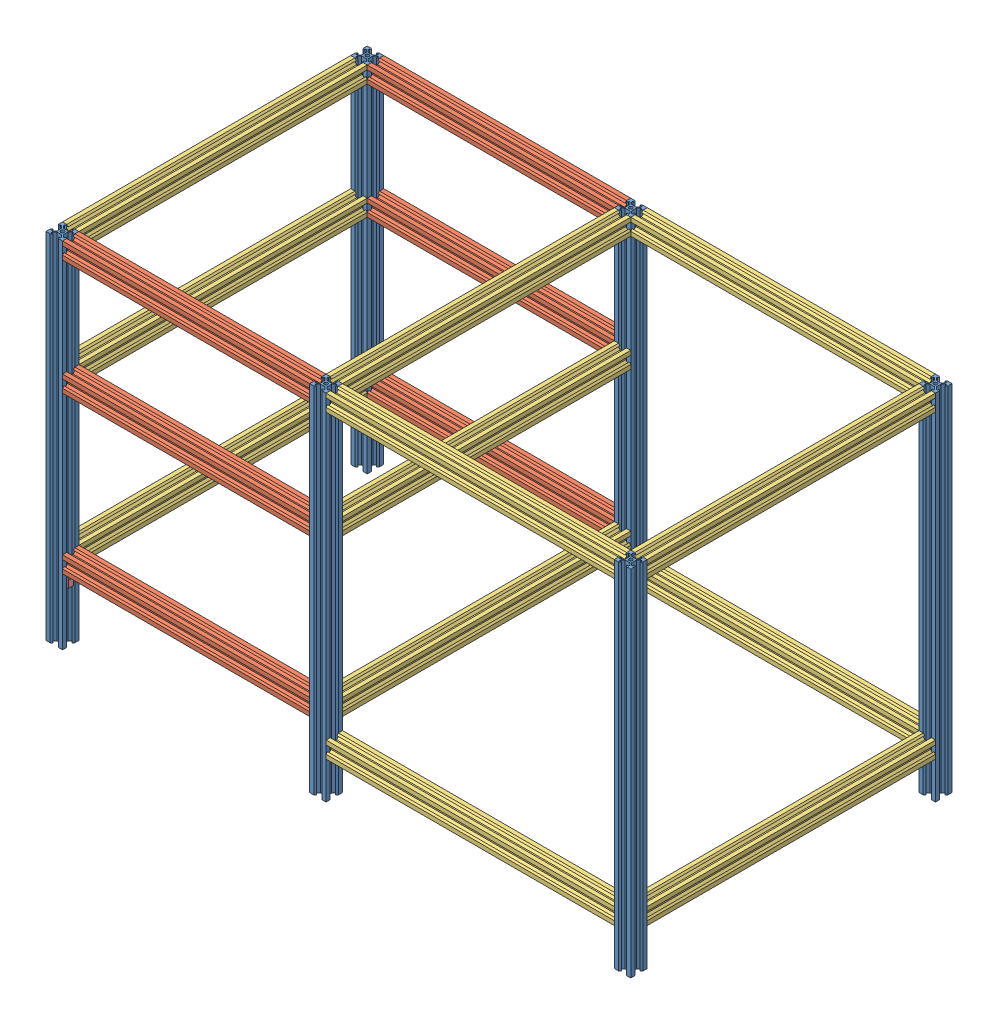
SolidWorks assembly total, configuration 默认. Lengths in mm.
Overall size (710 430 390).
28 component instances, 4 part files, 80 mates.
Components (placement in the parent):
- 2020lv_400-1: 2020lv_400 [默认] at (-104.4028 -206.392 400) size (20 430 20)
- 2020lv_400-2: 2020lv_400 [默认] at (215.5972 -206.392 30) size (20 430 20)
- 2020lv_400-3: 2020lv_400 [默认] at (-104.4028 -206.392 30) size (20 430 20)
- 2020lv_400-4: 2020lv_400 [默认] at (215.5972 -206.392 400) size (20 430 20)
- 2020lv_300-1: 2020lv_300 [默认] at (205.5972 -116.392 400) x (0 1 0) z (0 0 1) size (20 300 20)
- 2020lv_350-1: 2020lv_350 [默认] at (-104.4028 -116.392 40) x (-1 0 0) z (0 1 0) size (20 350 20)
- 2020lv_300-2: 2020lv_300 [默认] at (205.5972 -116.392 30) x (0 1 0) z (0 0 1) size (20 300 20)
- 2020lv_350-3: 2020lv_350 [默认] at (215.5972 -116.392 40) x (-1 0 0) z (0 1 0) size (20 350 20)
- 2020jiaocao-1: 2020jiaocao [默认] at (-104.5028 -123.392 40) x (0 -1 0) z (-1 0 0) size (25 26 10)
- 2020jiaocao-2: 2020jiaocao [默认] at (-104.5028 -123.392 390) x (0 -1 0) z (1 0 0) size (25 26 10)
- 2020jiaocao-3: 2020jiaocao [默认] at (-94.4028 -123.392 29.9) x (0 -1 0) z (0 0 1) size (25 26 10)
- 2020jiaocao-4: 2020jiaocao [默认] at (-94.4028 -123.392 399.9) x (0 -1 0) z (0 0 1) size (25 26 10)
- 2020lv_300-3: 2020lv_300 [默认] at (205.5972 73.608 400) x (0 1 0) z (0 0 1) size (20 300 20)
- 2020lv_300-4: 2020lv_300 [默认] at (205.5972 73.608 30) x (0 1 0) z (0 0 1) size (20 300 20)
- 2020lv_350-4: 2020lv_350 [默认] at (215.5972 73.608 40) x (-1 0 0) z (0 1 0) size (20 350 20)
- 2020lv_350-5: 2020lv_350 [默认] at (-104.4028 73.608 40) x (-1 0 0) z (0 1 0) size (20 350 20)
- 2020lv_350-6: 2020lv_350 [默认] at (215.5972 213.608 40) x (-1 0 0) z (0 1 0) size (20 350 20)
- 2020lv_350-7: 2020lv_350 [默认] at (-104.4028 213.608 40) x (-1 0 0) z (0 1 0) size (20 350 20)
- 2020lv_300-5: 2020lv_300 [默认] at (205.5972 213.608 30) x (0 1 0) z (0 0 1) size (20 300 20)
- 2020lv_300-6: 2020lv_300 [默认] at (205.5972 213.608 400) x (0 1 0) z (0 0 1) size (20 300 20)
- 2020lv_350-9: 2020lv_350 [默认] at (575.5972 -151.237 400) x (0 1 0) z (0 0 1) size (20 350 20)
- 2020lv_400-5: 2020lv_400 [默认] at (585.5972 -206.392 400) size (20 430 20)
- 2020lv_400-6: 2020lv_400 [默认] at (585.5972 -206.392 30) size (20 430 20)
- 2020lv_350-10: 2020lv_350 [默认] at (575.5972 -151.237 30) x (0 1 0) z (0 0 1) size (20 350 20)
- 2020lv_350-11: 2020lv_350 [默认] at (575.5972 213.608 400) x (0 1 0) z (0 0 1) size (20 350 20)
- 2020lv_350-12: 2020lv_350 [默认] at (575.5972 213.608 30) x (0 1 0) z (0 0 1) size (20 350 20)
- 2020lv_350-14: 2020lv_350 [默认] at (585.5972 213.608 40) x (-1 0 0) z (0 1 0) size (20 350 20)
- 2020lv_350-15: 2020lv_350 [默认] at (585.5972 -151.237 40) x (-1 0 0) z (0 1 0) size (20 350 20)
Mates (geometry in assembly coordinates):
- 重合1: coincident aligned: plane of 2020lv_400-1 through (-104.4028 -206.392 400) normal (0 -1 0); plane of 2020lv_400-3 through (-104.4028 -206.392 30) normal (0 -1 0)
- 重合2: coincident aligned: plane of 2020lv_400-3 through (-104.4028 -206.392 30) normal (0 -1 0); plane of 2020lv_400-4 through (215.5972 -206.392 400) normal (0 -1 0)
- 重合3: coincident aligned: plane of 2020lv_400-2 through (215.5972 -206.392 30) normal (0 -1 0); plane of 2020lv_400-4 through (215.5972 -206.392 400) normal (0 -1 0)
- 重合4: coincident aligned: plane of 2020lv_400-1 through (-94.4028 223.608 410) normal (0 0 1); plane of 2020lv_400-4 through (225.5972 223.608 410) normal (0 0 1)
- 重合5: coincident aligned: plane of 2020lv_400-2 through (225.5972 223.608 40) normal (1 0 0); plane of 2020lv_400-4 through (225.5972 223.608 390) normal (1 0 0)
- 重合6: coincident aligned: plane of 2020lv_400-2 through (205.5972 223.608 20) normal (0 0 -1); plane of 2020lv_400-3 through (-114.4028 223.608 20) normal (0 0 -1)
- 重合7: coincident aligned: plane of 2020lv_400-1 through (-114.4028 223.608 410) normal (-1 0 0); plane of 2020lv_400-3 through (-114.4028 223.608 40) normal (-1 0 0)
- 重合8: coincident aligned: plane of 2020lv_400-1 through (-94.4028 223.608 410) normal (0 0 1); plane of 2020lv_300-1 through (-94.4028 -106.392 410) normal (0 0 1)
- 重合9: coincident anti-aligned: plane of 2020lv_400-1 through (-94.4028 223.608 410) normal (1 0 0); plane of 2020lv_300-1 through (-94.4028 -116.392 400) normal (-1 0 0)
- 重合10: coincident anti-aligned: plane of 2020lv_400-4 through (205.5972 223.608 390) normal (-1 0 0); plane of 2020lv_300-1 through (205.5972 -116.392 400) normal (1 0 0)
- 重合12: coincident aligned: plane of 2020lv_300-1 through (-94.4028 -106.392 390) normal (0 1 0); plane of 2020lv_350-1 through (-114.4028 -106.392 390) normal (0 1 0)
- 重合13: coincident anti-aligned: plane of 2020lv_400-1 through (-94.4028 223.608 390) normal (0 0 -1); plane of 2020lv_350-1 through (-104.4028 -116.392 390) normal (0 0 1)
- 重合14: coincident aligned: plane of 2020lv_400-1 through (-114.4028 223.608 390) normal (-1 0 0); plane of 2020lv_350-1 through (-114.4028 -106.392 390) normal (-1 0 0)
- 重合15: coincident anti-aligned: plane of 2020lv_400-3 through (-114.4028 223.608 40) normal (0 0 1); plane of 2020lv_350-1 through (-104.4028 -116.392 40) normal (0 0 -1)
- 重合16: coincident aligned: plane of 2020lv_400-3 through (-114.4028 223.608 40) normal (0 0 1); plane of 2020lv_300-2 through (-94.4028 -106.392 40) normal (0 0 1)
- 重合17: coincident aligned: plane of 2020lv_350-1 through (-94.4028 -106.392 390) normal (0 1 0); plane of 2020lv_300-2 through (-94.4028 -106.392 40) normal (0 1 0)
- 重合18: coincident anti-aligned: plane of 2020lv_400-3 through (-94.4028 223.608 40) normal (1 0 0); plane of 2020lv_300-2 through (-94.4028 -116.392 30) normal (-1 0 0)
- 重合19: coincident aligned: plane of 2020lv_300-1 through (-94.4028 -106.392 390) normal (0 1 0); plane of 2020lv_350-3 through (205.5972 -106.392 390) normal (0 1 0)
- 重合20: coincident anti-aligned: plane of 2020lv_400-4 through (205.5972 223.608 390) normal (0 0 -1); plane of 2020lv_350-3 through (215.5972 -116.392 390) normal (0 0 1)
- 重合21: coincident aligned: plane of 2020lv_400-2 through (225.5972 223.608 20) normal (1 0 0); plane of 2020lv_350-3 through (225.5972 -106.392 390) normal (1 0 0)
- 重合22: coincident aligned: plane of 2020lv_400-3 through (-94.4028 223.608 40) normal (0 0 1); plane of 2020jiaocao-1 through (-107.5028 -145.392 40) normal (0 0 1)
- 重合23: coincident: line of 2020lv_400-3 through (-107.5028 223.608 38.2) axis (0 -1 0); plane of 2020jiaocao-1 through (-107.5028 -124.592 60) normal (-1 0 0)
- 重合24: coincident aligned: plane of 2020lv_350-1 through (-94.4028 -126.392 390) normal (0 -1 0); plane of 2020jiaocao-1 through (-107.5028 -126.392 60) normal (0 -1 0)
- 重合25: coincident aligned: plane of 2020jiaocao-1 through (-107.5028 -124.592 60) normal (-1 0 0); plane of 2020jiaocao-2 through (-107.5028 -124.592 370) normal (-1 0 0)
- 重合26: coincident aligned: plane of 2020lv_400-1 through (-94.4028 223.608 390) normal (0 0 -1); plane of 2020jiaocao-2 through (-101.5028 -145.392 390) normal (0 0 -1)
- 重合27: coincident aligned: plane of 2020lv_350-1 through (-114.4028 -126.392 390) normal (0 -1 0); plane of 2020jiaocao-2 through (-101.5028 -126.392 370) normal (0 -1 0)
- 重合28: coincident aligned: plane of 2020lv_400-3 through (-94.4028 223.608 40) normal (1 0 0); plane of 2020jiaocao-3 through (-94.4028 -145.392 32.9) normal (1 0 0)
- 重合29: coincident aligned: plane of 2020lv_300-2 through (-94.4028 -126.392 20) normal (0 -1 0); plane of 2020jiaocao-3 through (-74.4028 -126.392 32.9) normal (0 -1 0)
- 重合30: coincident: line of 2020lv_400-3 through (-96.2028 223.608 26.9) axis (0 -1 0); plane of 2020jiaocao-3 through (-74.4028 -124.592 26.9) normal (0 0 -1)
- 重合31: coincident aligned: plane of 2020lv_400-1 through (-94.4028 223.608 410) normal (1 0 0); plane of 2020jiaocao-4 through (-94.4028 -145.392 402.9) normal (1 0 0)
- 重合32: coincident aligned: plane of 2020lv_300-1 through (-94.4028 -126.392 390) normal (0 -1 0); plane of 2020jiaocao-4 through (-74.4028 -126.392 402.9) normal (0 -1 0)
- 重合33: coincident: line of 2020lv_300-1 through (-94.4028 -124.592 396.9) axis (1 0 0); plane of 2020jiaocao-4 through (-74.4028 -124.592 396.9) normal (0 0 -1)
- 距离1: distance = 80 mm aligned: plane of 2020lv_300-1 through (-94.4028 -126.392 390) normal (0 -1 0); plane of 2020lv_400-1 through (-104.4028 -206.392 400) normal (0 -1 0)
- 重合35: coincident aligned: plane of 2020lv_300-1 through (-94.4028 -106.392 410) normal (0 0 1); plane of 2020lv_300-3 through (-94.4028 83.608 410) normal (0 0 1)
- 重合36: coincident anti-aligned: plane of 2020lv_400-4 through (205.5972 223.608 390) normal (-1 0 0); plane of 2020lv_300-3 through (205.5972 73.608 400) normal (1 0 0)
- 重合37: coincident aligned: plane of 2020lv_300-3 through (-94.4028 83.608 390) normal (0 1 0); plane of 2020lv_300-4 through (-94.4028 83.608 40) normal (0 1 0)
- 重合38: coincident aligned: plane of 2020lv_400-2 through (205.5972 223.608 40) normal (0 0 1); plane of 2020lv_300-4 through (-94.4028 83.608 40) normal (0 0 1)
- 重合39: coincident anti-aligned: plane of 2020lv_400-3 through (-94.4028 223.608 20) normal (1 0 0); plane of 2020lv_300-4 through (-94.4028 73.608 30) normal (-1 0 0)
- 重合40: coincident anti-aligned: plane of 2020lv_400-4 through (205.5972 223.608 390) normal (0 0 -1); plane of 2020lv_350-4 through (215.5972 73.608 390) normal (0 0 1)
- 重合41: coincident aligned: plane of 2020lv_300-3 through (-94.4028 83.608 390) normal (0 1 0); plane of 2020lv_350-4 through (205.5972 83.608 390) normal (0 1 0)
- 重合42: coincident aligned: plane of 2020lv_400-4 through (225.5972 223.608 390) normal (1 0 0); plane of 2020lv_350-4 through (225.5972 83.608 390) normal (1 0 0)
- 重合44: coincident aligned: plane of 2020lv_300-3 through (-94.4028 83.608 390) normal (0 1 0); plane of 2020lv_350-5 through (-94.4028 83.608 390) normal (0 1 0)
- 重合45: coincident anti-aligned: plane of 2020lv_300-3 through (-94.4028 63.608 390) normal (0 0 -1); plane of 2020lv_350-5 through (-104.4028 73.608 390) normal (0 0 1)
- 重合46: coincident aligned: plane of 2020lv_400-1 through (-114.4028 223.608 410) normal (-1 0 0); plane of 2020lv_350-5 through (-114.4028 83.608 390) normal (-1 0 0)
- 距离2: distance = 170 mm anti-aligned: plane of 2020lv_350-4 through (225.5972 63.608 390) normal (0 -1 0); plane of 2020lv_350-3 through (205.5972 -106.392 390) normal (0 1 0)
- 重合48: coincident aligned: plane of 2020lv_400-4 through (225.5972 223.608 390) normal (1 0 0); plane of 2020lv_350-6 through (225.5972 223.608 390) normal (1 0 0)
- 重合49: coincident anti-aligned: plane of 2020lv_400-2 through (205.5972 223.608 40) normal (0 0 1); plane of 2020lv_350-6 through (215.5972 213.608 40) normal (0 0 -1)
- 重合50: coincident anti-aligned: plane of 2020lv_400-3 through (-114.4028 223.608 40) normal (0 0 1); plane of 2020lv_350-7 through (-104.4028 213.608 40) normal (0 0 -1)
- 重合51: coincident aligned: plane of 2020lv_400-3 through (-114.4028 223.608 20) normal (-1 0 0); plane of 2020lv_350-7 through (-114.4028 223.608 390) normal (-1 0 0)
- 重合52: coincident aligned: plane of 2020lv_350-6 through (225.5972 223.608 390) normal (0 1 0); plane of 2020lv_350-7 through (-94.4028 223.608 390) normal (0 1 0)
- 重合53: coincident aligned: plane of 2020lv_350-7 through (-114.4028 223.608 390) normal (0 1 0); plane of 2020lv_300-5 through (-94.4028 223.608 40) normal (0 1 0)
- 重合54: coincident anti-aligned: plane of 2020lv_400-2 through (205.5972 223.608 40) normal (-1 0 0); plane of 2020lv_300-5 through (205.5972 213.608 30) normal (1 0 0)
- 重合55: coincident aligned: plane of 2020lv_400-2 through (205.5972 223.608 20) normal (0 0 -1); plane of 2020lv_300-5 through (-94.4028 223.608 20) normal (0 0 -1)
- 重合56: coincident aligned: plane of 2020lv_350-6 through (205.5972 223.608 390) normal (0 1 0); plane of 2020lv_300-6 through (-94.4028 223.608 390) normal (0 1 0)
- 重合57: coincident anti-aligned: plane of 2020lv_400-1 through (-94.4028 223.608 390) normal (1 0 0); plane of 2020lv_300-6 through (-94.4028 213.608 400) normal (-1 0 0)
- 重合58: coincident aligned: plane of 2020lv_400-1 through (-94.4028 223.608 410) normal (0 0 1); plane of 2020lv_300-6 through (-94.4028 223.608 410) normal (0 0 1)
- 距离3: distance = 120 mm anti-aligned: plane of 2020lv_300-5 through (-94.4028 203.608 20) normal (0 -1 0); plane of 2020lv_300-4 through (-94.4028 83.608 40) normal (0 1 0)
- 重合63: coincident aligned: plane of 2020lv_400-4 through (225.5972 223.608 410) normal (0 0 1); plane of 2020lv_350-9 through (225.5972 -161.237 410) normal (0 0 1)
- 重合64: coincident anti-aligned: plane of 2020lv_400-4 through (225.5972 223.608 390) normal (1 0 0); plane of 2020lv_350-9 through (225.5972 -151.237 400) normal (-1 0 0)
- 重合65: coincident aligned: plane of 2020lv_400-4 through (225.5972 223.608 410) normal (0 0 1); plane of 2020lv_400-5 through (595.5972 223.608 410) normal (0 0 1)
- 重合66: coincident aligned: plane of 2020lv_400-4 through (215.5972 223.608 400) normal (0 1 0); plane of 2020lv_400-5 through (585.5972 223.608 400) normal (0 1 0)
- 重合67: coincident anti-aligned: plane of 2020lv_350-9 through (575.5972 -151.237 400) normal (1 0 0); plane of 2020lv_400-5 through (575.5972 223.608 410) normal (-1 0 0)
- 重合68: coincident aligned: plane of 2020lv_400-5 through (595.5972 223.608 410) normal (1 0 0); plane of 2020lv_400-6 through (595.5972 223.608 40) normal (1 0 0)
- 重合69: coincident aligned: plane of 2020lv_400-5 through (585.5972 223.608 400) normal (0 1 0); plane of 2020lv_400-6 through (585.5972 223.608 30) normal (0 1 0)
- 重合70: coincident aligned: plane of 2020lv_400-2 through (205.5972 223.608 40) normal (0 0 1); plane of 2020lv_400-6 through (575.5972 223.608 40) normal (0 0 1)
- 重合71: coincident aligned: plane of 2020lv_400-2 through (205.5972 223.608 40) normal (0 0 1); plane of 2020lv_350-10 through (225.5972 -141.237 40) normal (0 0 1)
- 重合72: coincident anti-aligned: plane of 2020lv_400-6 through (575.5972 223.608 40) normal (-1 0 0); plane of 2020lv_350-10 through (575.5972 -151.237 30) normal (1 0 0)
- 重合73: coincident aligned: plane of 2020lv_350-9 through (225.5972 -141.237 390) normal (0 1 0); plane of 2020lv_350-10 through (225.5972 -141.237 20) normal (0 1 0)
- 重合74: coincident aligned: plane of 2020lv_400-5 through (585.5972 223.608 400) normal (0 1 0); plane of 2020lv_350-11 through (225.5972 223.608 410) normal (0 1 0)
- 重合75: coincident anti-aligned: plane of 2020lv_400-5 through (575.5972 223.608 390) normal (-1 0 0); plane of 2020lv_350-11 through (575.5972 213.608 400) normal (1 0 0)
- 重合76: coincident aligned: plane of 2020lv_400-5 through (575.5972 223.608 410) normal (0 0 1); plane of 2020lv_350-11 through (225.5972 223.608 410) normal (0 0 1)
- 重合77: coincident aligned: plane of 2020lv_400-2 through (215.5972 223.608 30) normal (0 1 0); plane of 2020lv_350-12 through (225.5972 223.608 20) normal (0 1 0)
- 重合78: coincident anti-aligned: plane of 2020lv_400-6 through (575.5972 223.608 20) normal (-1 0 0); plane of 2020lv_350-12 through (575.5972 213.608 30) normal (1 0 0)
- 重合79: coincident aligned: plane of 2020lv_400-6 through (575.5972 223.608 20) normal (0 0 -1); plane of 2020lv_350-12 through (225.5972 223.608 20) normal (0 0 -1)
- 重合81: coincident anti-aligned: plane of 2020lv_400-5 through (575.5972 223.608 390) normal (0 0 -1); plane of 2020lv_350-14 through (585.5972 213.608 390) normal (0 0 1)
- 重合82: coincident aligned: plane of 2020lv_400-5 through (595.5972 223.608 390) normal (1 0 0); plane of 2020lv_350-14 through (595.5972 223.608 390) normal (1 0 0)
- 重合83: coincident aligned: plane of 2020lv_350-11 through (225.5972 223.608 410) normal (0 1 0); plane of 2020lv_350-14 through (575.5972 223.608 390) normal (0 1 0)
- 重合85: coincident aligned: plane of 2020lv_400-5 through (595.5972 223.608 390) normal (1 0 0); plane of 2020lv_350-15 through (595.5972 -141.237 390) normal (1 0 0)
- 重合87: coincident anti-aligned: plane of 2020lv_400-5 through (575.5972 223.608 390) normal (0 0 -1); plane of 2020lv_350-15 through (585.5972 -151.237 390) normal (0 0 1)
- 重合88: coincident aligned: plane of 2020lv_350-9 through (225.5972 -141.237 390) normal (0 1 0); plane of 2020lv_350-15 through (595.5972 -141.237 390) normal (0 1 0)
